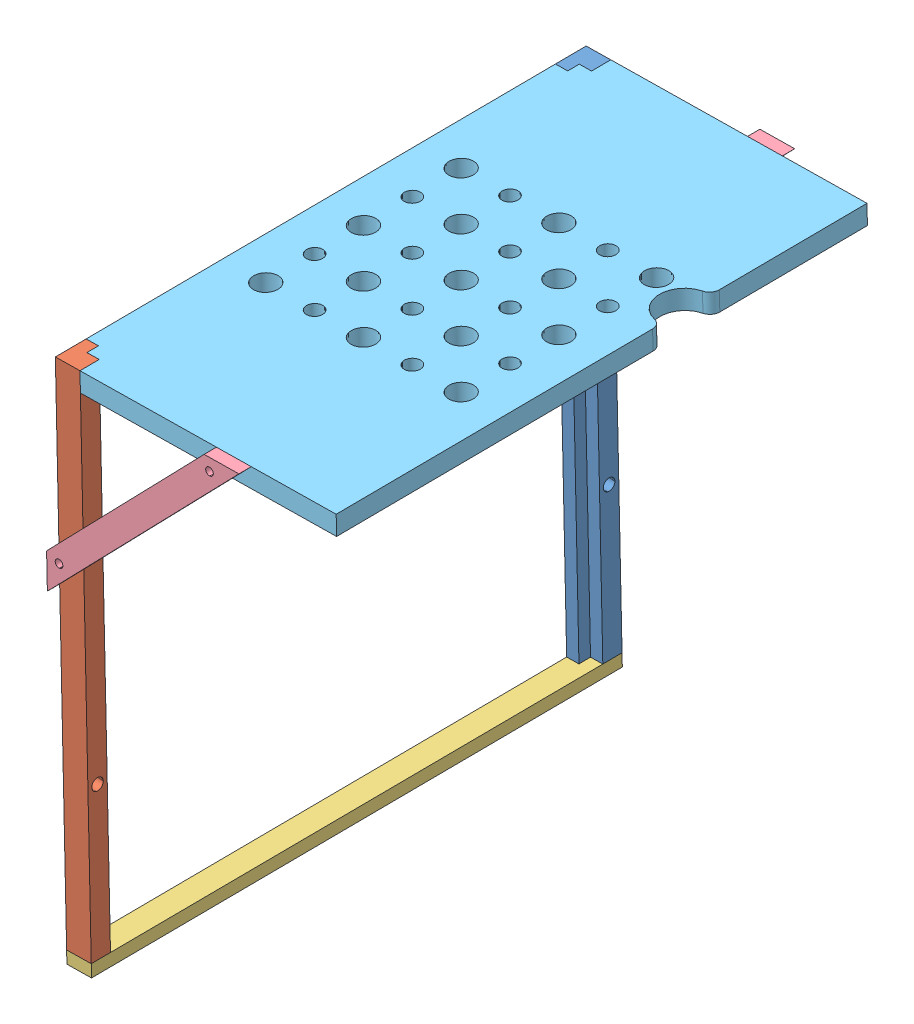
SolidWorks assembly Assem1, configuration Default. Lengths in mm.
Overall size (73.09 138.25 144.76).
7 component instances, 6 part files, 17 mates.
Components (placement in the parent):
- Bracket1-1: Bracket1 [Default] at (26.7317 -37.4674 55.4456) x (-0.000155 0.007146 -0.999974) z (-0.99989 -0.014864 0.000049) size (8 133 6.4)
- ConnectingBlock-1: ConnectingBlock [Default] at (61.2608 95.5997 120.3927) x (-0.000155 0.007146 -0.999974) z (0.014863 -0.999864 -0.007147) size (138 73 6.4) (hidden)
- Bracket2-1: Bracket2 [Default] at (26.7516 -38.3821 183.4423) x (-0.000155 0.007146 -0.999974) z (0.014863 -0.999864 -0.007147) size (8 6.4 133)
- FixedPlate-1: FixedPlate [Default] at (29.965 -39.477 119.4323) x (-0.014863 0.999864 0.007147) z (0.000155 -0.007146 0.999974) size (3.2 6.4 138)
- FixedDiagonalBlock-1: FixedDiagonalBlock [Default] at (28.0826 92.3994 51.3732) x (-0.014863 0.999864 0.007147) z (-0.000155 0.007146 -0.999974) size (55.45 55.45 3.2)
- FixedDiagonalBlock-2: FixedDiagonalBlock [Default] at (28.0232 91.3892 192.5696) x (-0.014863 0.999864 0.007147) z (-0.000155 0.007146 -0.999974) size (55.45 55.45 3.2)
- ConnectingBlockNoHoles-1: ConnectingBlockNoHoles [Default] at (61.2608 95.5997 120.3927) x (0.000155 -0.007146 0.999974) z (-0.014863 0.999864 0.007147) size (138 73 5)
Mates (geometry in assembly coordinates):
- Coincident1: coincident anti-aligned: plane of Bracket1-1 through (33.1302 -37.3366 50.4454) normal (0.99989 0.014864 -0.000049); plane of ConnectingBlock-1 through (31.1542 95.6096 56.3958) normal (-0.99989 -0.014864 0.000049)
- Coincident3: coincident anti-aligned: plane of Bracket1-1 through (29.9318 -37.4413 58.4453) normal (0.000155 -0.007146 0.999974); plane of ConnectingBlock-1 through (24.7553 95.493 59.3961) normal (-0.000155 0.007146 -0.999974)
- Coincident4: coincident aligned: plane of Bracket1-1 through (24.7549 95.5145 56.3962) normal (-0.014863 0.999864 0.007147); plane of ConnectingBlock-1 through (61.2608 95.5997 120.3927) normal (-0.014863 0.999864 0.007147)
- Coincident5: coincident aligned: plane of ConnectingBlock-1 through (61.2608 95.5997 120.3927) normal (-0.014863 0.999864 0.007147); plane of Bracket2-1 through (24.7748 94.5998 184.3929) normal (-0.014863 0.999864 0.007147)
- Coincident6: coincident anti-aligned: plane of ConnectingBlock-1 through (31.1748 94.6592 189.3924) normal (-0.99989 -0.014864 0.000049); plane of Bracket2-1 through (33.1509 -38.2869 183.442) normal (0.99989 0.014864 -0.000049)
- Coincident7: coincident anti-aligned: plane of ConnectingBlock-1 through (27.9739 94.6688 181.3928) normal (0.000155 -0.007146 0.999974); plane of Bracket2-1 through (26.7511 -38.3606 180.4424) normal (-0.000155 0.007146 -0.999974)
- Coincident8: coincident anti-aligned: plane of Bracket1-1 through (26.7317 -37.4674 55.4456) normal (0.014863 -0.999864 -0.007147); plane of FixedPlate-1 through (33.1302 -37.3366 50.4454) normal (-0.014863 0.999864 0.007147)
- Coincident9: coincident aligned: plane of Bracket1-1 through (26.7309 -37.4317 50.4457) normal (-0.000155 0.007146 -0.999974); plane of FixedPlate-1 through (29.9543 -38.9839 50.4341) normal (-0.000155 0.007146 -0.999974)
- Coincident10: coincident aligned: plane of Bracket1-1 through (26.7321 -37.4889 58.4455) normal (-0.99989 -0.014864 0.000049); plane of FixedPlate-1 through (26.7309 -37.4317 50.4457) normal (-0.99989 -0.014864 0.000049)
- Coincident11: coincident anti-aligned: plane of ConnectingBlock-1 through (24.7541 95.5502 51.3963) normal (-0.000155 0.007146 -0.999974); plane of FixedDiagonalBlock-1 through (28.0826 92.3994 51.3732) normal (0.000155 -0.007146 0.999974)
- Coincident12: coincident aligned: plane of ConnectingBlock-1 through (61.2608 95.5997 120.3927) normal (-0.014863 0.999864 0.007147); plane of FixedDiagonalBlock-1 through (66.7063 96.1739 51.3942) normal (-0.014863 0.999864 0.007147)
- Coincident13: coincident anti-aligned: plane of ConnectingBlock-1 through (97.7675 95.6492 189.3892) normal (0.000155 -0.007146 0.999974); plane of FixedDiagonalBlock-2 through (28.0227 91.4121 189.3697) normal (-0.000155 0.007146 -0.999974)
- Coincident14: coincident aligned: plane of ConnectingBlock-1 through (61.2608 95.5997 120.3927) normal (-0.014863 0.999864 0.007147); plane of FixedDiagonalBlock-2 through (66.6469 95.1637 192.5906) normal (-0.014863 0.999864 0.007147)
- Coincident15: coincident aligned: plane of Bracket2-1 through (26.7516 -38.3821 183.4423) normal (-0.99989 -0.014864 0.000049); plane of FixedDiagonalBlock-2 through (25.5329 43.6227 192.2287) normal (-0.99989 -0.014864 0.000049)
- Coincident17: coincident aligned: plane of ConnectingBlock-1 through (24.7755 94.5641 189.3928) normal (-0.99989 -0.014864 0.000049); plane of ConnectingBlockNoHoles-1 through (24.8297 90.4937 59.3603) normal (-0.99989 -0.014864 0.000049)
- Coincident18: coincident aligned: plane of ConnectingBlock-1 through (24.7541 95.5502 51.3963) normal (-0.000155 0.007146 -0.999974); plane of ConnectingBlockNoHoles-1 through (97.8204 91.636 51.357) normal (-0.000155 0.007146 -0.999974)
- Coincident19: coincident aligned: plane of ConnectingBlock-1 through (61.2608 95.5997 120.3927) normal (-0.014863 0.999864 0.007147); plane of ConnectingBlockNoHoles-1 through (95.2523 96.324 89.7581) normal (-0.014863 0.999864 0.007147)
